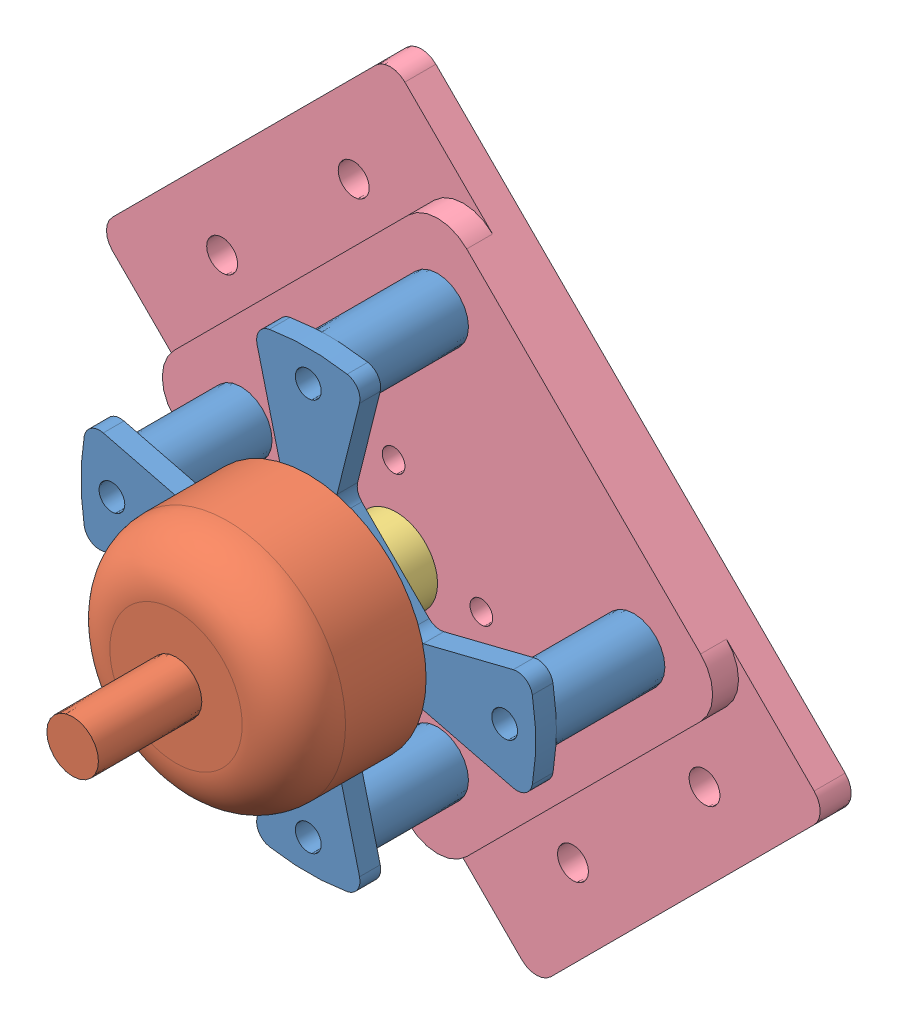
SolidWorks assembly 电机_固定座_装配体, configuration 默认. Lengths in mm.
Overall size (70.71 70.71 40.8).
4 component instances, 4 part files, 7 mates.
Components (placement in the parent):
- B2212电机固定-1: B2212电机固定 [默认] at (-10.0704 -0.2098 48.25) size (44 44 12.5)
- 1804无刷电机-1: 1804无刷电机 [默认] at (-10.0704 -0.2098 50.25) size (22.8 22.8 24.3)
- 磁铁安装件-1: 磁铁安装件 [默认] at (-10.0704 -0.2098 45.75) x (-0.755076 -0.655637 0) z (0 0 -1) size (8 8 8)
- 底座-1: 底座 [默认] at (26.698 26.7503 35.25) x (0.707107 0.707107 0) z (0 0 1) size (40 60 5.5)
Mates (geometry in assembly coordinates):
- 同心1: concentric: circle of assembly; circle of assembly; circle of B2212电机固定-1; circle of 1804无刷电机-1
- 重合1: coincident: plane of assembly; plane of assembly; plane of B2212电机固定-1 through (-10.0704 -0.2098 50.25) normal (0 0 1); plane of 1804无刷电机-1 through (-10.0704 -0.2098 50.25) normal (0 0 -1)
- 同心2: concentric: circle of assembly; circle of assembly; circle of 1804无刷电机-1; circle of 磁铁安装件-1
- 重合2: coincident: plane of assembly; plane of assembly; plane of 1804无刷电机-1 through (-10.0704 -0.2098 49.75) normal (0 0 -1); plane of 磁铁安装件-1 through (-10.0704 -0.2098 49.75) normal (0 0 1)
- 同心3: concentric: circle of assembly; circle of assembly; circle of B2212电机固定-1; circle of 底座-1
- 同心4: concentric: circle of assembly; circle of assembly; circle of B2212电机固定-1; circle of 底座-1
- 重合3: coincident: plane of assembly; plane of assembly; plane of B2212电机固定-1 through (-29.0704 -0.2098 37.75) normal (0 0 -1); plane of 底座-1 through (26.698 26.7503 37.75) normal (0 0 1)
